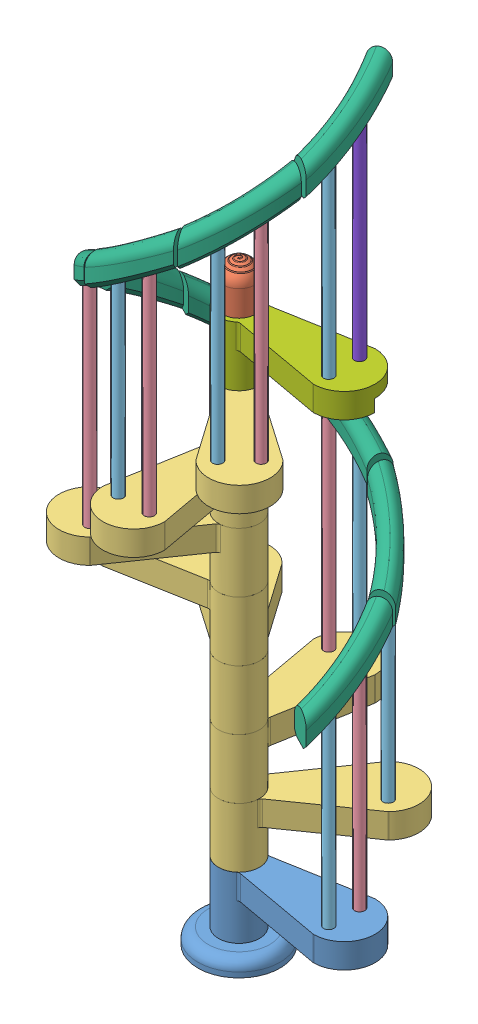
SolidWorks assembly Final_Stair_Assembly, configuration Default. Lengths in mm.
Overall size (1327.83 3937.2 1327.08).
37 component instances, 8 part files, 24 mates.
Components (placement in the parent):
- Stair_Base-1: Stair_Base [Default] at (119.8116 217.5723 603.7629) size (863.54 500 400)
- End Cap-1: End Cap [Default] at (119.8109 2962.5723 604.064) x (1 0 0) z (0 1 0) size (155.48 155.48 203.3)
- Step-1: Step [Default] at (119.8116 517.5723 603.7629) x (0.707107 0 -0.707107) z (0.707107 0 0.707107) size (763.54 415 299.98)
- Railing_Pole_Large-1: Railing_Pole_Large [Default] at (633.5175 417.5723 530.2115) x (0.952996 0 -0.302983) z (0.302983 0 0.952996) size (50 1175 50)
- Railing_Pole_Small-1: Railing_Pole_Small [Default] at (633.1824 417.5723 680.2111) x (-0.592312 0 -0.805709) z (0.805709 0 -0.592312) size (50 1100 50)
- Railing_Pole_Large-2: Railing_Pole_Large [Default] at (428.7535 707.5723 186.7455) x (0.952064 0 -0.3059) z (0.3059 0 0.952064) size (50 1175 50)
- Railing_Pole_Small-2: Railing_Pole_Small [Default] at (535.1126 707.5723 292.5175) x (0.604354 0 -0.796716) z (0.796716 0 0.604354) size (50 1100 50)
- Railing_Pole_Large-10: Railing_Pole_Large [Default] at (43.3906 997.5723 90.4321) x (0.456907 0 -0.889515) z (0.889515 0 0.456907) size (50 1175 50)
- Railing_Pole_Large-11: Railing_Pole_Large [Default] at (-297.2059 1287.5723 294.821) x (-0.3059 0 -0.952064) z (0.952064 0 -0.3059) size (50 1175 50)
- Railing_Pole_Large-12: Railing_Pole_Large [Default] at (-393.5193 1577.5723 680.1839) x (-0.889515 0 -0.456907) z (0.456907 0 -0.889515) size (50 1175 50)
- Railing_Pole_Large-13: Railing_Pole_Large [Default] at (-189.1303 1867.5723 1020.7804) x (-0.952064 0 0.3059) z (-0.3059 0 -0.952064) size (50 1175 50)
- Railing_Pole_Large-14: Railing_Pole_Large [Default] at (196.2325 2157.5723 1117.0937) x (-0.456907 0 0.889515) z (-0.889515 0 -0.456907) size (50 1175 50)
- Railing_Pole_Large-15: Railing_Pole_Large [Default] at (536.829 2447.5723 912.7048) x (0.3059 0 0.952064) z (-0.952064 0 0.3059) size (50 1175 50)
- Railing_Pole_Small-10: Railing_Pole_Small [Default] at (193.39 997.5723 90.017) x (-0.13602 0 -0.990706) z (0.990706 0 -0.13602) size (50 1100 50)
- Railing_Pole_Small-11: Railing_Pole_Small [Default] at (-191.4339 1287.5723 188.4619) x (-0.796716 0 -0.604354) z (0.604354 0 -0.796716) size (50 1100 50)
- Railing_Pole_Small-12: Railing_Pole_Small [Default] at (-393.9344 1577.5723 530.1845) x (-0.990706 0 0.13602) z (-0.13602 0 -0.990706) size (50 1100 50)
- Railing_Pole_Small-13: Railing_Pole_Small [Default] at (-295.4895 1867.5723 915.0084) x (-0.604354 0 0.796716) z (-0.796716 0 -0.604354) size (50 1100 50)
- Railing_Pole_Small-14: Railing_Pole_Small [Default] at (46.2331 2157.5723 1117.5089) x (0.13602 0 0.990706) z (-0.990706 0 0.13602) size (50 1100 50)
- Railing_Pole_Small-15: Railing_Pole_Small [Default] at (431.057 2447.5723 1019.064) x (0.796716 0 0.604354) z (-0.604354 0 0.796716) size (50 1100 50)
- Step-9: Step [Default] at (119.8116 807.5723 603.7629) x (0 0 -1) z (1 0 0) size (763.54 415 299.98)
- Step-10: Step [Default] at (119.8116 1097.5723 603.7629) x (-0.707107 0 -0.707107) z (0.707107 0 -0.707107) size (763.54 415 299.98)
- Step-11: Step [Default] at (119.8116 1387.5723 603.7629) x (-1 0 0) z (0 0 -1) size (763.54 415 299.98)
- Step-12: Step [Default] at (119.8116 1677.5723 603.7629) x (-0.707107 0 0.707107) z (-0.707107 0 -0.707107) size (763.54 415 299.98)
- Step-13: Step [Default] at (119.8116 1967.5723 603.7629) x (0 0 1) z (-1 0 0) size (763.54 415 299.98)
- Step-14: Step [Default] at (119.8116 2257.5723 603.7629) x (0.707107 0 0.707107) z (-0.707107 0 0.707107) size (763.54 415 299.98)
- Railing_Handle-2: Railing_Handle [Default] at (273.4907 1322.5723 604.4074) x (0.999998 0 0.002234) z (-0.002234 0 0.999998) size (138.11 431.31 433.58)
- Railing_Handle-10: Railing_Handle [Default] at (228.9348 1612.5723 495.551) x (0.708685 0 -0.705525) z (0.705525 0 0.708685) size (138.11 431.31 433.58)
- Railing_Handle-11: Railing_Handle [Default] at (120.456 1902.5723 450.0838) x (0.002234 0 -0.999998) z (0.999998 0 0.002234) size (138.11 431.31 433.58)
- Railing_Handle-12: Railing_Handle [Default] at (11.5996 2192.5723 494.6397) x (-0.705525 0 -0.708685) z (0.708685 0 -0.705525) size (138.11 431.31 433.58)
- Railing_Handle-13: Railing_Handle [Default] at (-33.8676 2482.5723 603.1185) x (-0.999998 0 -0.002234) z (0.002234 0 -0.999998) size (138.11 431.31 433.58)
- Railing_Handle-14: Railing_Handle [Default] at (10.6883 2772.5723 711.9749) x (-0.708685 0 0.705525) z (-0.705525 0 -0.708685) size (138.11 431.31 433.58)
- Railing_Handle-15: Railing_Handle [Default] at (119.1671 3062.5723 757.4421) x (-0.002234 0 0.999998) z (-0.999998 0 -0.002234) size (138.11 431.31 433.58)
- Railing_Handle-16: Railing_Handle [Default] at (228.0235 3352.5723 712.8862) x (0.705525 0 0.708685) z (-0.708685 0 0.705525) size (138.11 431.31 433.58)
- Railing_Handle-17: Railing_Handle [Default] at (273.4907 3642.5723 604.4074) x (0.999998 0 0.002234) z (-0.002234 0 0.999998) size (138.11 431.31 433.58)
- Last Step-3: Last Step [Default] at (119.8109 2547.5723 604.064) x (0.999987 0 0.005002) z (-0.005002 0 0.999987) size (763.54 415 299.98)
- Railing_Pole_Last Step-3: Railing_Pole_Last Step [Default] at (633.5175 2777.5723 530.2115) x (-0.10415 0 0.994562) z (-0.994562 0 -0.10415) size (50 1151.63 50)
- Railing_Pole_Small-17: Railing_Pole_Small [Default] at (633.1824 2717.5723 680.2111) x (0.229606 0 -0.973284) z (0.973284 0 0.229606) size (50 1100 50)
Mates (geometry in assembly coordinates):
- Concentric1: concentric aligned: circle of Stair_Base-1; circle of Step-1
- Coincident6: coincident anti-aligned: plane of Stair_Base-1 through (119.8116 517.5723 603.7629) normal (0 1 0); plane of Step-1 through (119.8116 517.5723 603.7629) normal (0 -1 0)
- Concentric2: concentric aligned: circle of Stair_Base-1; circle of Railing_Pole_Small-1
- Coincident9: coincident anti-aligned: plane of Stair_Base-1 through (633.1824 417.5723 680.2111) normal (0 1 0); plane of Railing_Pole_Small-1 through (633.1824 417.5723 680.2111) normal (0 -1 0)
- Concentric3: concentric aligned: circle of Stair_Base-1; circle of Railing_Pole_Large-1
- Coincident11: coincident anti-aligned: plane of Stair_Base-1 through (633.5175 417.5723 530.2115) normal (0 1 0); plane of Railing_Pole_Large-1 through (633.5175 417.5723 530.2115) normal (0 -1 0)
- Concentric4: concentric aligned: circle of Step-1; circle of Railing_Pole_Small-2
- Coincident14: coincident anti-aligned: plane of Step-1 through (535.1126 707.5723 292.5175) normal (0 1 0); plane of Railing_Pole_Small-2 through (535.1126 707.5723 292.5175) normal (0 -1 0)
- Concentric5: concentric aligned: circle of Step-1; circle of Railing_Pole_Large-2
- Coincident16: coincident anti-aligned: plane of Step-1 through (428.7535 707.5723 186.7455) normal (0 1 0); plane of Railing_Pole_Large-2 through (428.7535 707.5723 186.7455) normal (0 -1 0)
- Concentric15: concentric aligned: cylinder of Railing_Handle-2 through (633.5175 1612.5723 530.2115) axis (0 -1 0) radius 25; cylinder of Railing_Pole_Large-1 through (633.5175 1592.5723 530.2115) axis (0 -1 0) radius 25
- Distance5: distance = 20 mm anti-aligned: plane of Railing_Handle-2 through (633.5175 1612.5723 530.2115) normal (0 -1 0); plane of Railing_Pole_Large-1 through (633.5175 1592.5723 530.2115) normal (0 1 0)
- Concentric20: concentric anti-aligned: cylinder of Railing_Pole_Small-16 through (633.5575 2837.5723 677.3414) axis (0 -1 0) radius 25; circle of Last Step-3
- Coincident20: coincident anti-aligned: plane of Railing_Pole_Small-16 through (633.5575 2737.5723 677.3414) normal (0 -1 0); plane of Last Step-3 through (633.1824 2737.5723 680.2111) normal (0 1 0)
- Concentric22: concentric anti-aligned: circle of Last Step-3; cylinder of Railing_Pole_Last Step-3 through (633.5175 2877.5723 530.2115) axis (0 -1 0) radius 25
- Coincident22: coincident aligned: plane of Last Step-3 through (119.8109 2777.5723 604.064) normal (0 -1 0); plane of Railing_Pole_Last Step-3 through (633.5175 2777.5723 530.2115) normal (0 -1 0)
- Coincident26: coincident anti-aligned: plane of Step-14 through (119.8116 2547.5723 603.7629) normal (0 1 0); plane of Last Step-3 through (119.8109 2547.5723 604.064) normal (0 -1 0)
- Coincident27: coincident aligned: plane of Last Step-3 through (633.3499 2717.5723 605.2113) normal (0 -1 0); plane of Railing_Pole_Small-17 through (633.1824 2717.5723 680.2111) normal (0 -1 0)
- Concentric27: concentric aligned: cylinder of Railing_Handle-17 through (633.1824 3792.5723 680.2111) axis (0 -1 0) radius 25; cylinder of Railing_Pole_Small-17 through (633.1824 2817.5723 680.2111) axis (0 -1 0) radius 25
- Concentric29: concentric anti-aligned: circle of Last Step-3; cylinder of Railing_Pole_Small-17 through (633.1824 2817.5723 680.2111) axis (0 -1 0) radius 25
- Concentric30: concentric aligned: cylinder of Railing_Handle-17 through (633.5175 3932.5723 530.2115) axis (0 -1 0) radius 25; cylinder of Railing_Pole_Last Step-3 through (633.5175 2877.5723 530.2115) axis (0 -1 0) radius 25
- Concentric31: concentric aligned: cylinder of Railing_Pole_Small-1 through (633.1824 517.5723 680.2111) axis (0 -1 0) radius 25; cylinder of Railing_Handle-2 through (633.1824 1472.5723 680.2111) axis (0 -1 0) radius 15
- Concentric33: concentric: cylinder of End Cap-1 through (119.8109 3158.755 604.064) axis (0 1 0) radius 77.2391; cylinder of Last Step-3 through (119.8109 2837.5723 604.064) axis (0 -1 0) radius 100
- Coincident29: coincident aligned: circle of End Cap-1; plane of Last Step-3 through (119.8109 2837.5723 604.064) normal (0 1 0)
